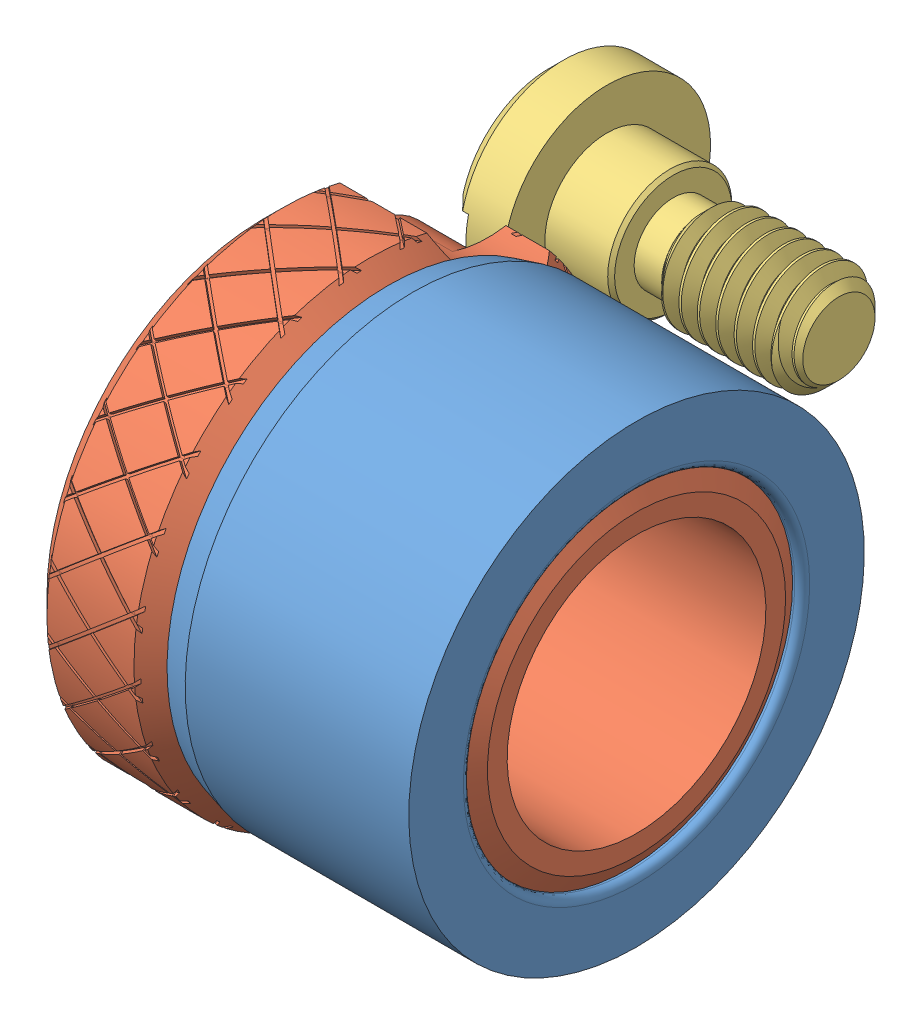
SolidWorks assembly 19MM Bushing, configuration Default. Lengths in mm.
Overall size (28.57 49.02 54.37).
3 component instances, 3 part files, 4 mates.
Components (placement in the parent):
- 3556N198_Sleeve for Removable Drill Bushing-1: 3556N198_Sleeve for Removable Drill Bushing [3556N198] at (-3.1895 22.8435 32.2329)
- 8493A272_Removable Drill Bushing-1: 8493A272_Removable Drill Bushing [8493A272] at (-7.952 22.8435 32.2329) x (1 0 0) z (0 0.529453 0.848339)
- 8496A15_Lock Screw for Removable Drill Bushings-1: 8496A15_Lock Screw for Removable Drill Bushings [8496A15] at (-10.8095 32.0046 10.6838)
Mates (geometry in assembly coordinates):
- Concentric1: concentric aligned: cylinder of 3556N198_Sleeve for Removable Drill Bushing-1 through (-12.7145 22.8435 32.2329) axis (-1 0 0) radius 17.4625; cylinder of 8493A272_Removable Drill Bushing-1 through (-22.2395 22.8435 32.2329) axis (-1 0 0) radius 12.7
- Coincident1: coincident anti-aligned: plane of 3556N198_Sleeve for Removable Drill Bushing-1 through (-12.7145 39.7956 32.2329) normal (-1 0 0); plane of 8493A272_Removable Drill Bushing-1 through (-12.7145 38.1627 22.6722) normal (1 0 0)
- Coincident2: coincident anti-aligned: plane of 8493A272_Removable Drill Bushing-1 through (-17.477 38.1627 22.6722) normal (-1 0 0); plane of 8496A15_Lock Screw for Removable Drill Bushings-1 through (-17.477 32.0046 10.6838) normal (1 0 0)
- Concentric2: concentric anti-aligned: cylinder of 8493A272_Removable Drill Bushing-1 through (10.8587 32.0046 10.6838) axis (-1 0 0) radius 8.3344; cylinder of 8496A15_Lock Screw for Removable Drill Bushings-1 through (-21.922 32.0046 10.6838) axis (1 0 0) radius 7.9375
